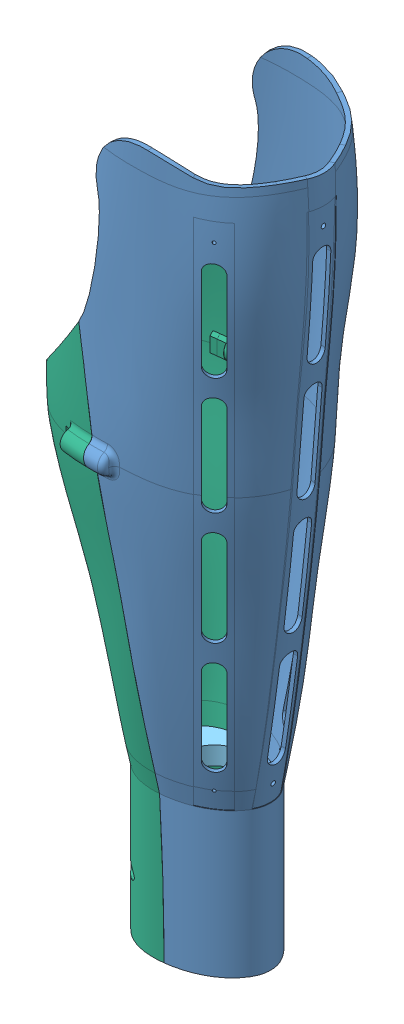
SolidWorks assembly COVER ASSEMBLY, configuration Default. Lengths in mm.
Overall size (170.61 403.59 114.88).
9 component instances, 6 part files, 9 mates.
Components (placement in the parent):
- FRONT-1: FRONT [Default] at origin size (170.61 403.59 114.88)
- Cover Upper Part_Insert_94510A040 (M4)-1: Cover Upper Part_Insert_94510A040 (M4) [94510A040] at (-19.2755 163.2864 -45.2114) x (0 -0.380885 -0.924623) z (0 0.924623 -0.380885) size (5.99 8.2 5.97)
- Cover Upper Part_Insert_94510A040 (M4)-2: Cover Upper Part_Insert_94510A040 (M4) [94510A040] at (-19.2755 163.2806 45.2255) x (0 0.380885 -0.924623) z (0 0.924623 0.380885) size (5.99 8.2 5.97)
- Disk_Inserts_95110A101 (M3)-1: Disk_Inserts_95110A101 (M3) [95110A101] at (-4.2275 -5 20.0177) x (0 0.141497 0.989939) z (0 -0.989939 0.141497) size (5.5 5.08 5.5)
- Disk_Inserts_95110A101 (M3)-2: Disk_Inserts_95110A101 (M3) [95110A101] at (-4.2275 -5 -20.0177) x (0 -0.141497 0.989939) z (0 -0.989939 -0.141497) size (5.5 5.08 5.5)
- Cover Lower Part_Insert_ 94510A035(M 3.5)-1: Cover Lower Part_Insert_ 94510A035(M 3.5) [94510A035] at (-2.3145 -50.0001 20.1127) x (0 0.381179 0.924501) z (0 -0.924501 0.381179) size (5.2 6.57 5.49)
- Cover Lower Part_Insert_ 94510A035(M 3.5)-2: Cover Lower Part_Insert_ 94510A035(M 3.5) [94510A035] at (-2.3145 -49.996 -20.1226) x (0 -0.381179 0.924501) z (0 -0.924501 -0.381179) size (5.2 6.57 5.49)
- back disc-1: back disc [Default] at (0 0 0) x (1 0 0) z (0 0 1) size (141.21 243.19 85.8)
- BACK-2: BACK [Default] at (0 0 0) size (141.21 301.33 102.95)
Mates (geometry in assembly coordinates):
- Concentric7: concentric anti-aligned: cylinder of FRONT-1 through (-30.8149 163.2864 -45.2114) axis (1 0 0) radius 2.921; cylinder of Cover Upper Part_Insert_94510A040 (M4)-1 through (-11.3253 163.2864 -45.2114) axis (-1 0 0) radius 2.7686
- Coincident2: coincident anti-aligned: plane of FRONT-1 through (-11.3253 163.2864 -45.2114) normal (-1 0 0); plane of Cover Upper Part_Insert_94510A040 (M4)-1 through (-11.3253 163.2864 -45.2114) normal (1 0 0)
- Concentric9: concentric aligned: cylinder of FRONT-1 through (0.5725 -5 20.0177) axis (-1 0 0) radius 2.1082; cylinder of Disk_Inserts_95110A101 (M3)-1 through (-3.7175 -5 20.0177) axis (-1 0 0) radius 2.75
- Coincident3: coincident anti-aligned: plane of FRONT-1 through (0.5725 -5 20.0177) normal (-1 0 0); plane of Disk_Inserts_95110A101 (M3)-1 through (0.5725 -5 20.0177) normal (1 0 0)
- Concentric10: concentric aligned: cylinder of FRONT-1 through (4.0355 -50.0001 20.1127) axis (-1 0 0) radius 2.5273; cylinder of Cover Lower Part_Insert_ 94510A035(M 3.5)-1 through (4.0355 -50.0001 20.1127) axis (-1 0 0) radius 2.3749
- Coincident5: coincident anti-aligned: plane of FRONT-1 through (4.0355 -50.0001 20.1127) normal (-1 0 0); plane of Cover Lower Part_Insert_ 94510A035(M 3.5)-2 through (4.0355 -49.996 -20.1226) normal (1 0 0)
- Coincident6: coincident aligned: circle of Disk_Inserts_95110A101 (M3)-1; circle of back disc-1
- Concentric13: concentric anti-aligned: circle of FRONT-1; circle of BACK (1) (1)-2
- Coincident7: coincident anti-aligned: plane of FRONT-1 through (-2.3145 -45 -23.3839) normal (-1 0 0); plane of BACK (1) (1)-2 through (-2.3145 -45 -23.3839) normal (1 0 0)
